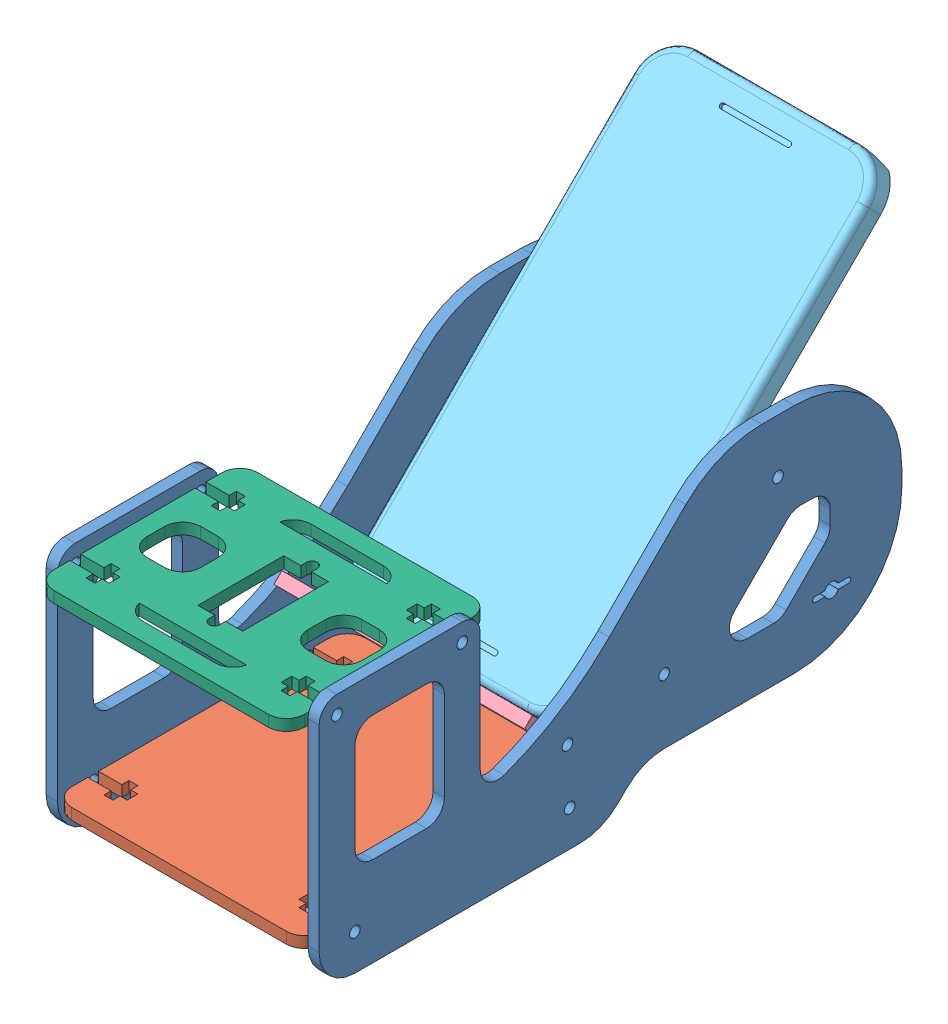
SolidWorks assembly robo_assy, configuration Default. Lengths in mm.
Overall size (76.25 118.72 181.71).
7 component instances, 6 part files, 18 mates.
Components (placement in the parent):
- RobotSide-1: RobotSide [Default] at (143.0365 98.9062 72.0808) size (3.12 75.96 162.8)
- RobotSide-2: RobotSide [Default] at (69.9115 98.9062 72.0808) size (3.12 75.96 162.8)
- RobotBot-1: RobotBot [Default] at (108.0365 82.7749 175.285) size (70 3.12 82)
- Robophon-1: Robophon [Default] at (108.0365 117.8269 102.9702) x (1 0 0) z (0 -0.707107 0.707107) size (70 3.12 67)
- Robophon_bot-1: Robophon_bot [Default] at (108.0365 80.7038 128.2139) x (1 0 0) z (0 -0.707107 -0.707107) size (70 3.12 36)
- MOTO G-1: MOTO G [Default] at (75.5365 88.9239 134.2243) x (1 0 0) z (0 0.707107 0.707107) size (65 133.76 11.4)
- RoboServo-1: RoboServo [Default] at (108.0365 137.7749 192.785) size (70 3.12 57)
Mates (geometry in assembly coordinates):
- Concentric1: concentric aligned: cylinder of RobotSide-1 through (146.1615 82.7749 205.285) axis (-1 0 0) radius 1.5; cylinder of RobotSide-2 through (73.0365 82.7749 205.285) axis (-1 0 0) radius 1.5
- Concentric2: concentric aligned: cylinder of RobotSide-1 through (146.1615 133.7368 87.0603) axis (-1 0 0) radius 1.5; cylinder of RobotSide-2 through (73.0365 133.7368 87.0603) axis (-1 0 0) radius 1.5
- Coincident1: coincident anti-aligned: plane of RobotSide-1 through (143.0365 98.9062 72.0808) normal (-1 0 0); plane of RobotBot-1 through (143.0365 84.3374 216.285) normal (1 0 0)
- Coincident2: coincident anti-aligned: plane of RobotSide-2 through (73.0365 98.9062 72.0808) normal (1 0 0); plane of RobotBot-1 through (73.0365 84.3374 216.285) normal (-1 0 0)
- Concentric3: concentric anti-aligned: cylinder of RobotSide-1 through (146.1615 82.7749 145.285) axis (-1 0 0) radius 1.5; line of RobotBot-1 through (108.0365 82.7749 145.285) axis (1 0 0)
- Parallel1: parallel aligned: plane of RobotBot-1 through (108.0365 84.3374 175.285) normal (0 1 0); plane of RobotSide-1 through (146.1615 142.7749 215.285) normal (0 1 0)
- Parallel2: parallel aligned: plane of RobotSide-1 through (146.1615 148.7368 104.0215) normal (0 0.707107 0.707107); plane of Robophon-1 through (108.0365 118.9317 104.0751) normal (0 0.707107 0.707107)
- Concentric4: concentric anti-aligned: cylinder of RobotSide-1 through (146.1615 133.7368 87.0603) axis (-1 0 0) radius 1.5; line of Robophon-1 through (108.0365 133.7368 87.0603) axis (1 0 0)
- Coincident7: coincident anti-aligned: plane of RobotSide-1 through (143.0365 98.9062 72.0808) normal (-1 0 0); plane of Robophon-1 through (143.0365 133.781 89.2258) normal (1 0 0)
- Concentric5: concentric anti-aligned: cylinder of RobotSide-1 through (146.1615 98.3815 145.8916) axis (-1 0 0) radius 1.5; line of Robophon_bot-1 through (108.0365 98.3815 145.8916) axis (1 0 0)
- Coincident9: coincident anti-aligned: plane of RobotSide-1 through (143.0365 98.9062 72.0808) normal (-1 0 0); plane of Robophon_bot-1 through (143.0365 96.2159 145.9358) normal (1 0 0)
- Parallel3: parallel anti-aligned: line of RobotSide-2 through (69.9115 98.3815 145.8916) axis (0 -0.707107 -0.707107); line of Robophon_bot-1 through (73.0365 81.8086 127.1091) axis (0 0.707107 0.707107)
- Coincident11: coincident anti-aligned: plane of Robophon-1 through (108.0365 118.9317 104.0751) normal (0 0.707107 0.707107); plane of MOTO G-1 through (108.0365 165.9278 57.079) normal (0 -0.707107 -0.707107)
- Distance1: distance = 2.5 mm anti-aligned: plane of MOTO G-1 through (140.5365 96.9142 142.2146) normal (1 0 0); plane of RobotSide-1 through (143.0365 98.9062 72.0808) normal (-1 0 0)
- Tangent1: tangent anti-aligned: plane of Robophon_bot-1 through (108.0365 81.8086 127.1091) normal (0 0.707107 -0.707107); cylinder of MOTO G-1 through (75.5365 96.9142 139.3862) axis (1 0 0) radius 2
- Concentric6: concentric anti-aligned: cylinder of RobotSide-1 through (146.1615 137.7749 175.285) axis (-1 0 0) radius 1.5; line of RoboServo-1 through (108.0365 137.7749 175.285) axis (1 0 0)
- Parallel4: parallel aligned: plane of RobotSide-1 through (146.1615 142.7749 215.285) normal (0 1 0); plane of RoboServo-1 through (108.0365 139.3374 192.785) normal (0 1 0)
- Coincident14: coincident anti-aligned: plane of RobotSide-1 through (143.0365 98.9062 72.0808) normal (-1 0 0); plane of RoboServo-1 through (143.0365 139.3374 176.785) normal (1 0 0)
